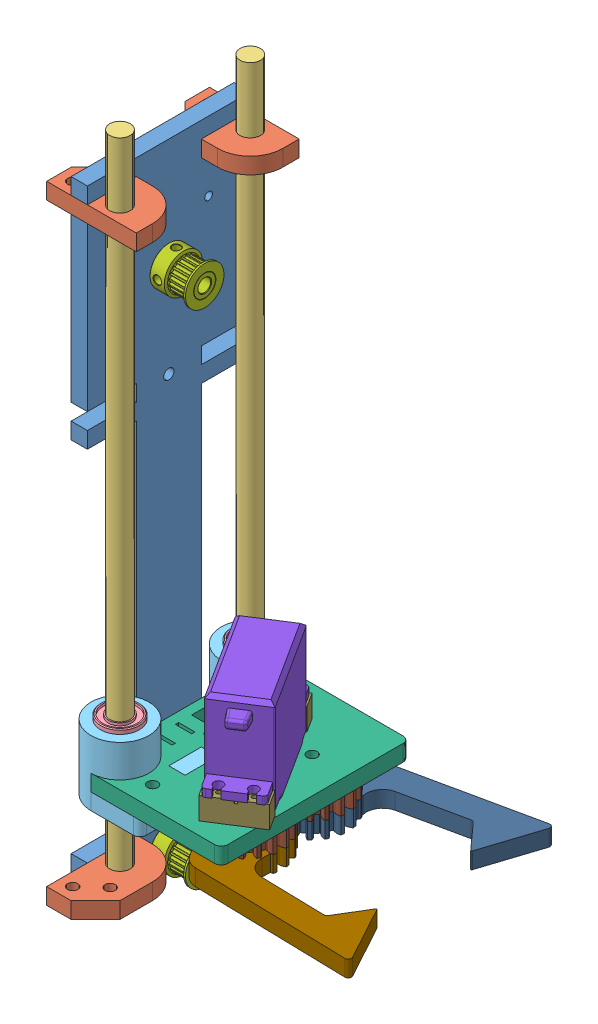
SolidWorks assembly PulleyModule, configuration Default. Lengths in mm.
Overall size (125.26 266.7 96.11).
19 component instances, 12 part files, 37 mates.
Components (placement in the parent):
- PulleyBoard-1: PulleyBoard [Default] at (39.7737 6.4419 232.4121) size (6.35 247.65 63.5)
- FrontBottom-1: FrontBottom [Default] at (39.7737 31.8419 340.3621) size (19.05 6.35 34.92)
- FrontBottom-2: FrontBottom [Default] at (39.7737 38.1919 60.9621) x (1 0 0) z (0 0 -1) size (19.05 6.35 34.92)
- Shaft8mm-1: Shaft8mm [Default] at (52.4737 31.8419 226.0621) size (8 254 8)
- Shaft8mm-2: Shaft8mm [Default] at (52.4737 31.8419 175.2621) x (0.997108 0 -0.075996) z (0.075996 0 0.997108) size (8 254 8)
- LM8UU-1: LM8UU [Default] at (52.4737 76.678 175.2621) x (0 -1 0) z (-0.618662 0 0.785658) size (24 15 15)
- LM8UU-2: LM8UU [Default] at (52.4737 76.678 226.0621) x (0 -1 0) z (0 0 1) size (24 15 15)
- 3DPrint-1: 3DPrint [Default] at (52.4737 61.503 200.6621) x (0 0 -1) z (1 0 0) size (73.42 6.35 41.67)
- ClampSupport-1: ClampSupport [Default] at (52.4737 67.853 200.6621) x (0 0 -1) z (1 0 0) size (73.42 6.35 73.42)
- GT2_20tooth-1: GT2_20tooth [Конфигурация1] at (46.1237 224.2919 200.6621) size (14 15 15)
- GT2_20tooth-2: GT2_20tooth [Конфигурация1] at (46.1237 28.6669 200.6621) size (14 15 15)
- power_hd_6001hb_servo-1: power_hd_6001hb_servo [Default] at (83.5903 112.303 204.4284) x (-0.538774 0 -0.84245) z (-0.84245 0 0.538774) size (54.5 43.74 20.07)
- GearL-1: GearL [Default] at (89.3037 55.153 213.3621) x (0.999717 0 0.023781) z (-0.023781 0 0.999717) size (78.19 6.35 36.83)
- GearR-1: GearR [Default] at (89.3037 55.153 187.9621) x (0.977961 0 -0.208788) z (0.208788 0 0.977961) size (78.31 6.35 36.71)
- Gear-1: Gear [Default] at (89.3037 61.503 213.3621) x (0.947561 0 -0.319576) z (0.319576 0 0.947561) size (27.7 6.35 27.94)
- Gear-2: Gear [Default] at (89.3037 61.503 187.9621) x (0.999359 0 -0.035795) z (0.035795 0 0.999359) size (27.7 6.35 27.94)
- 3DPart2-1: 3DPart2 [Default] at (106.4689 74.203 221.7031) x (-0.538774 0 -0.84245) z (0.84245 0 -0.538774) size (54.5 8.56 20)
- FrontBottom-3: FrontBottom [Default] at (-61.8263 254.0919 162.5621) x (0 0 1) z (-1 0 0) size (19.05 6.35 34.92)
- FrontBottom-4: FrontBottom [Default] at (-61.8263 260.4419 238.7621) x (0 0 -1) z (-1 0 0) size (19.05 6.35 34.92)
Mates (geometry in assembly coordinates):
- Coincident1: coincident anti-aligned: plane of PulleyBoard-1 through (46.1237 6.4419 232.4121) normal (1 0 0); plane of FrontBottom-1 through (46.1237 38.1919 340.3621) normal (-1 0 0)
- Coincident2: coincident anti-aligned: plane of PulleyBoard-1 through (46.1237 6.4419 232.4121) normal (1 0 0); plane of FrontBottom-2 through (46.1237 31.8419 60.9621) normal (-1 0 0)
- Coincident6: coincident aligned: plane of PulleyBoard-1 through (46.1237 31.8419 232.4121) normal (0 -1 0); plane of FrontBottom-1 through (39.7737 31.8419 340.3621) normal (0 -1 0)
- Coincident7: coincident aligned: plane of PulleyBoard-1 through (46.1237 31.8419 175.2621) normal (0 -1 0); plane of FrontBottom-2 through (39.7737 31.8419 60.9621) normal (0 -1 0)
- Concentric1: concentric anti-aligned: circle of FrontBottom-1; cylinder of Shaft8mm-1 through (52.4737 285.8419 226.0621) axis (0 -1 0) radius 4
- Coincident8: coincident anti-aligned: plane of FrontBottom-1 through (39.7737 31.8419 340.3621) normal (0 -1 0); circle of Shaft8mm-1
- Concentric2: concentric aligned: circle of FrontBottom-2; cylinder of Shaft8mm-2 through (52.4737 285.8419 175.2621) axis (0 -1 0) radius 4
- Coincident9: coincident aligned: plane of FrontBottom-2 through (39.7737 31.8419 60.9621) normal (0 -1 0); plane of Shaft8mm-2 through (52.4737 31.8419 175.2621) normal (0 -1 0)
- Concentric3: concentric anti-aligned: cylinder of Shaft8mm-1 through (52.4737 285.8419 226.0621) axis (0 -1 0) radius 4; cylinder of LM8UU-2 through (52.4737 122.3675 226.0621) axis (0 1 0) radius 4
- Concentric4: concentric anti-aligned: cylinder of Shaft8mm-2 through (52.4737 285.8419 175.2621) axis (0 -1 0) radius 4; cylinder of LM8UU-1 through (52.4737 122.3675 175.2621) axis (0 1 0) radius 4
- Coincident10: coincident aligned: plane of LM8UU-1 through (52.4737 64.678 175.2621) normal (0 -1 0); plane of LM8UU-2 through (52.4737 64.678 226.0621) normal (0 -1 0)
- Coincident14: coincident anti-aligned: plane of PulleyBoard-1 through (46.1237 6.4419 232.4121) normal (1 0 0); plane of GT2_20tooth-2 through (46.1237 28.6669 200.6621) normal (-1 0 0)
- Concentric9: concentric anti-aligned: circle of PulleyBoard-1; circle of GT2_20tooth-2
- Coincident15: coincident anti-aligned: plane of PulleyBoard-1 through (46.1237 6.4419 232.4121) normal (1 0 0); plane of GT2_20tooth-1 through (46.1237 224.2919 200.6621) normal (-1 0 0)
- Concentric11: concentric anti-aligned: circle of PulleyBoard-1; circle of GT2_20tooth-1
- Coincident20: coincident anti-aligned: plane of PulleyBoard-1 through (39.7737 177.8919 213.3621) normal (0 0 1); plane of FrontBottom-1 through (39.7737 38.1919 213.3621) normal (0 0 -1)
- Coincident22: coincident anti-aligned: plane of ClampSupport-1 through (52.4737 74.203 200.6621) normal (0 1 0); plane of power_hd_6001hb_servo-1 through (83.5903 74.203 204.4284) normal (0 -1 0)
- Concentric12: concentric anti-aligned: cylinder of ClampSupport-1 through (89.3037 67.853 213.3621) axis (0 1 0) radius 10.795; circle of power_hd_6001hb_servo-1
- Concentric14: concentric aligned: circle of ClampSupport-1; circle of GearR-1
- Concentric15: concentric aligned: circle of ClampSupport-1; circle of GearL-1
- Coincident28: coincident anti-aligned: plane of GearR-1 through (89.3037 61.503 187.9621) normal (0 1 0); plane of Gear-2 through (89.3037 61.503 187.9621) normal (0 -1 0)
- Concentric17: concentric aligned: circle of GearR-1; circle of Gear-2
- Concentric18: concentric aligned: cylinder of GearR-1 through (100.5291 61.503 182.4722) axis (0 -1 0) radius 4.0704; cylinder of Gear-2 through (100.5291 67.853 182.4722) axis (0 -1 0) radius 4.0704
- Coincident29: coincident anti-aligned: plane of GearL-1 through (89.3037 61.503 213.3621) normal (0 1 0); plane of Gear-1 through (89.3037 61.503 213.3621) normal (0 -1 0)
- Concentric19: concentric aligned: circle of GearL-1; circle of Gear-1
- Concentric20: concentric aligned: cylinder of GearL-1 through (101.3946 61.503 210.2066) axis (0 -1 0) radius 4.0704; cylinder of Gear-1 through (101.3946 67.853 210.2066) axis (0 -1 0) radius 4.0704
- Coincident31: coincident aligned: plane of Gear-1 through (89.3037 67.853 213.3621) normal (0 1 0); plane of Gear-2 through (89.3037 67.853 187.9621) normal (0 1 0)
- Coincident32: coincident anti-aligned: plane of ClampSupport-1 through (52.4737 67.853 200.6621) normal (0 -1 0); plane of Gear-1 through (89.3037 67.853 213.3621) normal (0 1 0)
- Coincident33: coincident anti-aligned: plane of ClampSupport-1 through (52.4737 74.203 200.6621) normal (0 1 0); plane of 3DPart2-1 through (106.4689 74.203 221.7031) normal (0 -1 0)
- Coincident34: coincident anti-aligned: plane of power_hd_6001hb_servo-1 through (85.9832 74.203 226.792) normal (0.538774 0 0.84245); plane of 3DPart2-1 through (102.8322 82.7628 216.0165) normal (-0.538774 0 -0.84245)
- Coincident35: coincident aligned: plane of power_hd_6001hb_servo-1 through (85.9832 74.203 226.792) normal (-0.84245 0 0.538774); plane of 3DPart2-1 through (89.6199 82.7628 232.4785) normal (-0.84245 0 0.538774)
- Coincident36: coincident anti-aligned: plane of PulleyBoard-1 through (39.7737 260.4419 187.9621) normal (0 -1 0); plane of FrontBottom-3 through (-61.8263 260.4419 162.5621) normal (0 1 0)
- Concentric21: concentric anti-aligned: cylinder of Shaft8mm-2 through (52.4737 285.8419 175.2621) axis (0 -1 0) radius 4; circle of FrontBottom-3
- Coincident37: coincident anti-aligned: plane of PulleyBoard-1 through (39.7737 260.4419 187.9621) normal (0 0 -1); plane of FrontBottom-3 through (-61.8263 260.4419 187.9621) normal (0 0 1)
- Coincident38: coincident anti-aligned: plane of PulleyBoard-1 through (39.7737 260.4419 232.4121) normal (0 -1 0); plane of FrontBottom-4 through (-61.8263 260.4419 238.7621) normal (0 1 0)
- Concentric22: concentric aligned: cylinder of Shaft8mm-1 through (52.4737 285.8419 226.0621) axis (0 -1 0) radius 4; circle of FrontBottom-4
- Coincident39: coincident anti-aligned: plane of PulleyBoard-1 through (39.7737 260.4419 213.3621) normal (0 0 1); plane of FrontBottom-4 through (-61.8263 254.0919 213.3621) normal (0 0 -1)
